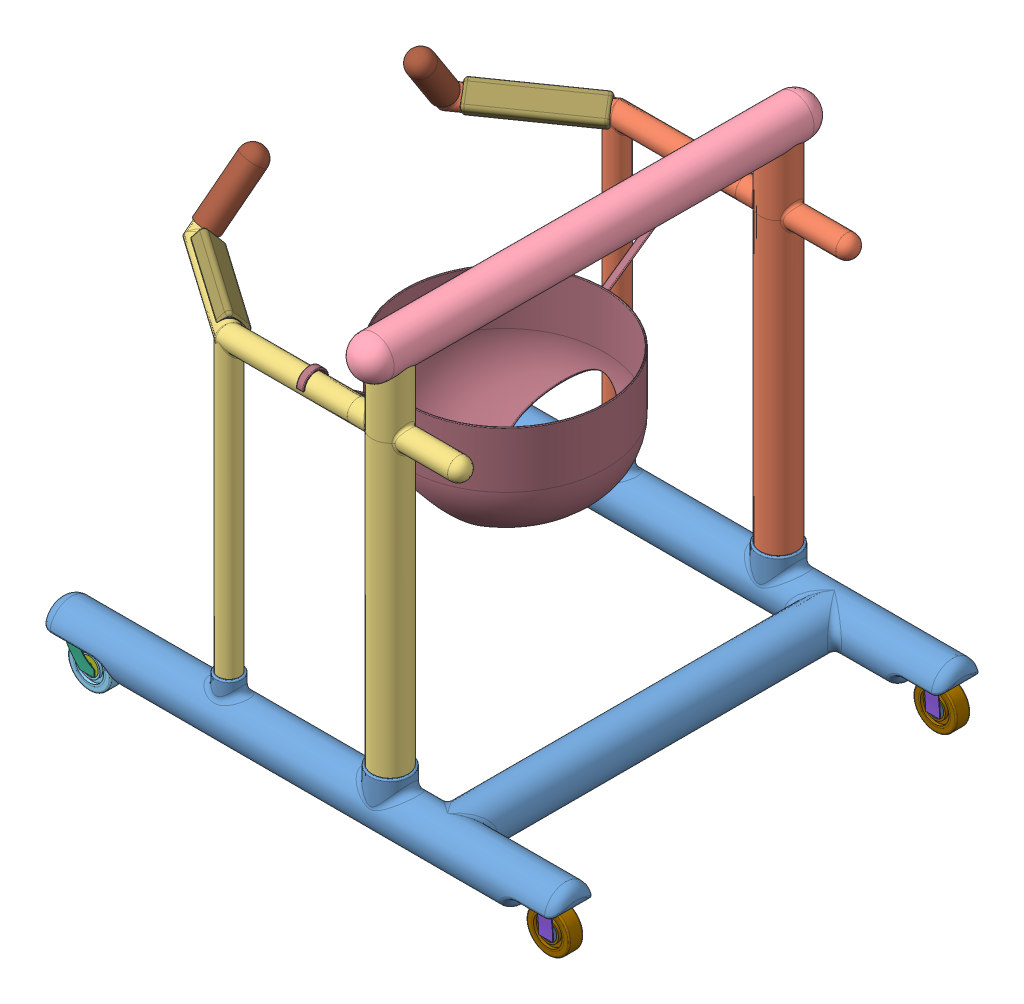
SolidWorks assembly Assem Collapse-Exploded Views, configuration Default. Lengths in mm.
Overall size (922.93 824.12 813.04).
41 component instances, 14 part files, 60 mates.
Components (placement in the parent):
- Base V5-1: Base V5 [Default] at (-126.4785 391.078 1010.3536) size (918.71 101.65 765.3)
- Side Left-1: Side Left [Default] at (402.939 968.928 324.5536) x (-1 0 0) z (0 0 -1) size (623.13 766.95 244.49)
- MirrorSide Left-3: MirrorSide Left [Default] at (400.5715 968.928 1010.3536) x (-1 0 0) z (0 0 -1) size (623.13 766.95 244.49)
- TopBarSupport-1: TopBarSupport [Default] at (457.5023 1094.5251 1073.8533) x (0.003452 0 -0.999994) z (0.999994 0 0.003452) size (812.8 71.12 71.12)
- Assem2 Front Wheel-1: Assem2 Front Wheel [Default] at (12.5906 315.4768 322.3492) x (0 0 1) z (-0.999997 0.002364 0) size (53.34 80.1 80.32)
  - Front Wheel-1: Front Wheel [Default] at (-10.3636 34.7825 75.6515) size (25.4 76.2 76.2)
  - Front Wheel Mountv2-1: Front Wheel Mountv2 [Default] at (18.654 50.0525 62.9876) x (1 0 0) z (0 -0.002364 0.999997) size (53.34 52.12 57.51)
  - Front Wheel BearingSet-1: Front Wheel BearingSet [Default] at (-10.3636 34.7825 75.6515) x (0 0.002364 -0.999997) z (1 0 0) size (31.75 31.75 25.4)
- Assem2 Front Wheel-2: Assem2 Front Wheel [Default] at (12.5906 315.4768 1008.1492) x (0 0 1) z (-0.999997 0.002364 0) size (53.34 80.1 80.32)
  - Front Wheel-1: Front Wheel [Default] at (-10.3636 34.7825 75.6515) size (25.4 76.2 76.2)
  - Front Wheel Mountv2-1: Front Wheel Mountv2 [Default] at (18.654 50.0525 62.9876) x (1 0 0) z (0 -0.002364 0.999997) size (53.34 52.12 57.51)
  - Front Wheel BearingSet-1: Front Wheel BearingSet [Default] at (-10.3636 34.7825 75.6515) x (0 0.002364 -0.999997) z (1 0 0) size (31.75 31.75 25.4)
- Assem2 Back Wheel-1: Assem2 Back Wheel [Default] at (706.4816 333.8846 330.834) x (0 0 -1) z (1 0 0) size (53.34 88.94 88.94)
  - Back Wheel Mountv2-1: Back Wheel Mountv2 [Default] at (22.7299 31.7935 30.6399) size (53.34 52.07 26.61)
  - Back Wheel-1: Back Wheel [Default] at (-6.5311 16.5535 43.3399) x (1 0 0) z (0 -0.184287 0.982872) size (25.4 76.2 76.2)
  - BackWheel Bairing Set-1: BackWheel Bairing Set [Default] at (18.8689 16.5535 43.3399) x (0 0 1) z (-1 0 0) size (31.75 31.75 25.4)
- Assem2 Back Wheel-2: Assem2 Back Wheel [Default] at (706.4816 333.8846 1016.634) x (0 0 -1) z (1 0 0) size (53.34 88.94 88.94)
  - Back Wheel Mountv2-1: Back Wheel Mountv2 [Default] at (22.7299 31.7935 30.6399) size (53.34 52.07 26.61)
  - Back Wheel-1: Back Wheel [Default] at (-6.5311 16.5535 43.3399) x (1 0 0) z (0 -0.184287 0.982872) size (25.4 76.2 76.2)
  - BackWheel Bairing Set-1: BackWheel Bairing Set [Default] at (18.8689 16.5535 43.3399) x (0 0 1) z (-1 0 0) size (31.75 31.75 25.4)
- Handle Covering v1-1: Handle Covering v1 [Default] at (-2.516 968.928 448.3888) x (0.979122 -0.193427 -0.062493) z (-0.062493 -0.578988 0.812937) size (43.18 127 43.18)
- Handle Covering v1-2: Handle Covering v1 [Default] at (-4.8834 968.928 886.5185) x (0.979122 -0.193427 0.062493) z (0.062493 0.578988 0.812937) size (43.18 127 43.18)
- Arm Covering v1-1: Arm Covering v1 [Default] at (88.3616 968.928 951.8093) x (0.819152 0 0.573576) z (-0.390769 0.732018 0.558076) size (190.83 24.3 45.72)
- Arm Covering v1-2: Arm Covering v1 [Default] at (92.2038 968.928 382.0653) x (0.819152 0 -0.573576) z (0.446291 -0.62816 0.637369) size (190.83 24.3 45.72)
- ChairPiece-1: ChairPiece [Default] at (318.9986 782.9456 667.2302) x (0 0.001708 0.999999) z (-1 0 0) size (730.43 346.85 355.6)
- WheelScrews-1: WheelScrews [Default] at (-97.2541 392.348 301.6936) x (-0.070113 0 0.997539) z (0.997539 0 0.070113) size (3.81 17.78 3.81)
- WheelScrews-2: WheelScrews [Default] at (-79.4885 392.348 301.6936) x (-0.070113 0 0.997539) z (0.997539 0 0.070113) size (3.81 17.78 3.81)
- WheelScrews-3: WheelScrews [Default] at (-79.4739 392.348 347.4136) x (-0.070113 0 0.997539) z (0.997539 0 0.070113) size (3.81 17.78 3.81)
- WheelScrews-4: WheelScrews [Default] at (-97.2685 392.348 347.4136) x (-0.070113 0 0.997539) z (0.997539 0 0.070113) size (3.81 17.78 3.81)
- WheelScrews-5: WheelScrews [Default] at (-79.4739 392.348 1033.2136) x (-0.070113 0 0.997539) z (0.997539 0 0.070113) size (3.81 17.78 3.81)
- WheelScrews-7: WheelScrews [Default] at (-97.2685 392.348 1033.2136) x (-0.070113 0 0.997539) z (0.997539 0 0.070113) size (3.81 17.78 3.81)
- WheelScrews-8: WheelScrews [Default] at (-79.4885 392.348 987.4936) x (-0.070113 0 0.997539) z (0.997539 0 0.070113) size (3.81 17.78 3.81)
- WheelScrews-9: WheelScrews [Default] at (-97.2541 392.348 987.4936) x (-0.070113 0 0.997539) z (0.997539 0 0.070113) size (3.81 17.78 3.81)
- WheelScrews-10: WheelScrews [Default] at (740.9315 392.348 347.4136) x (-0.837169 0 -0.546944) z (-0.546944 0 0.837169) size (3.81 17.78 3.81)
- WheelScrews-11: WheelScrews [Default] at (758.7115 392.348 347.4136) x (-0.837169 0 -0.546944) z (-0.546944 0 0.837169) size (3.81 17.78 3.81)
- WheelScrews-14: WheelScrews [Default] at (758.7115 392.348 301.6936) x (-0.837169 0 -0.546944) z (-0.546944 0 0.837169) size (3.81 17.78 3.81)
- WheelScrews-15: WheelScrews [Default] at (740.9315 392.348 301.6936) x (-0.837169 0 -0.546944) z (-0.546944 0 0.837169) size (3.81 17.78 3.81)
- WheelScrews-16: WheelScrews [Default] at (740.9315 392.348 1033.2136) x (-0.837169 0 -0.546944) z (-0.546944 0 0.837169) size (3.81 17.78 3.81)
- WheelScrews-18: WheelScrews [Default] at (758.7115 392.348 987.4936) x (-0.837169 0 -0.546944) z (-0.546944 0 0.837169) size (3.81 17.78 3.81)
- WheelScrews-19: WheelScrews [Default] at (740.9315 392.348 987.4936) x (-0.837169 0 -0.546944) z (-0.546944 0 0.837169) size (3.81 17.78 3.81)
- WheelScrews-20: WheelScrews [Default] at (758.7115 392.348 1033.2136) x (-0.837169 0 -0.546944) z (-0.546944 0 0.837169) size (3.81 17.78 3.81)
Mates (geometry in assembly coordinates):
- Tangent1: tangent aligned: cylinder of Base V5-1 through (635.5215 391.078 324.5536) axis (-1 0 0) radius 31.75; sphere of Side Left-1
- Concentric1: concentric aligned: cylinder of Base V5-1 through (460.089 352.977 324.5536) axis (0 1 0) radius 31.75; cylinder of Side Left-1 through (460.089 359.328 324.5536) axis (0 1 0) radius 31.75
- Concentric2: concentric anti-aligned: cylinder of Base V5-1 through (174.339 391.078 324.5536) axis (0 1 0) radius 19.05; cylinder of Side Left-1 through (174.339 968.928 324.5536) axis (0 -1 0) radius 19.05
- Tangent2: tangent aligned: cylinder of Base V5-1 through (635.5215 391.078 1010.3536) axis (-1 0 0) radius 31.75; sphere of MirrorSide Left-3
- Concentric3: concentric aligned: cylinder of Base V5-1 through (457.7215 352.977 1010.3536) axis (0 1 0) radius 31.75; cylinder of MirrorSide Left-3 through (457.7215 359.328 1010.3536) axis (0 1 0) radius 31.75
- Concentric4: concentric anti-aligned: cylinder of Base V5-1 through (171.9715 391.078 1010.3536) axis (0 1 0) radius 19.05; cylinder of MirrorSide Left-3 through (171.9715 968.928 1010.3536) axis (0 -1 0) radius 19.05
- Tangent3: tangent aligned: sphere of MirrorSide Left-3; cylinder of TopBarSupport-1 through (460.2205 1094.5251 286.458) axis (-0.003452 0 0.999994) radius 31.75
- Tangent4: tangent aligned: sphere of Side Left-1; cylinder of TopBarSupport-1 through (460.2205 1094.5251 286.458) axis (-0.003452 0 0.999994) radius 31.75
- Concentric5: concentric aligned: cylinder of MirrorSide Left-3 through (457.7215 968.928 1010.3536) axis (0 1 0) radius 31.75; cylinder of TopBarSupport-1 through (457.7215 1058.9641 1010.3536) axis (0 1 0) radius 31.75
- Concentric6: concentric: sphere of Side Left-1; sphere of Handle Covering v1-1
- Concentric7: concentric anti-aligned: cylinder of Side Left-1 through (-10.1378 937.7174 425.5741) axis (0.193427 0.79206 0.578988) radius 19.05; cylinder of Handle Covering v1-1 through (24.5058 1079.5788 529.2735) axis (-0.193427 -0.79206 -0.578988) radius 19.05
- Concentric8: concentric: sphere of MirrorSide Left-3; sphere of Handle Covering v1-2
- Concentric9: concentric anti-aligned: cylinder of MirrorSide Left-3 through (-12.5053 937.7174 909.3332) axis (0.193427 0.79206 -0.578988) radius 19.05; cylinder of Handle Covering v1-2 through (22.1383 1079.5788 805.6338) axis (-0.193427 -0.79206 0.578988) radius 19.05
- Concentric10: concentric aligned: cylinder of MirrorSide Left-3 through (184.1534 968.928 1018.8835) axis (-0.819152 0 -0.573576) radius 19.05; cylinder of Arm Covering v1-1 through (166.3866 968.928 1006.4431) axis (-0.819152 0 -0.573576) radius 19.05
- Concentric11: concentric aligned: cylinder of Side Left-1 through (186.5208 968.928 316.0238) axis (-0.819152 0 0.573576) radius 19.05; cylinder of Arm Covering v1-2 through (170.2288 968.928 327.4316) axis (-0.819152 0 0.573576) radius 19.05
- Coincident1: coincident anti-aligned: plane of Base V5-1 through (-126.4785 392.348 1010.3536) normal (0 -1 0); plane of Assem2 Front Wheel-1/Front Wheel Mountv2-1 through (-50.2785 392.348 341.0032) normal (0 1 0)
- Coincident2: coincident anti-aligned: plane of Base V5-1 through (-101.0785 392.348 297.8836) normal (0 0 1); plane of Assem2 Front Wheel-1/Front Wheel Mountv2-1 through (-50.2785 365.678 297.8836) normal (0 0 -1)
- Coincident3: coincident anti-aligned: plane of Base V5-1 through (-101.0785 392.348 351.2236) normal (1 0 0); plane of Assem2 Front Wheel-1/Front Wheel Mountv2-1 through (-101.0785 392.348 351.2236) normal (-1 0 0)
- Coincident4: coincident anti-aligned: plane of Base V5-1 through (-126.4785 392.348 1010.3536) normal (0 -1 0); plane of Assem2 Front Wheel-2/Front Wheel Mountv2-1 through (-50.2785 392.348 1026.8032) normal (0 1 0)
- Coincident5: coincident anti-aligned: plane of Base V5-1 through (-101.0785 392.348 1037.0236) normal (1 0 0); plane of Assem2 Front Wheel-2/Front Wheel Mountv2-1 through (-101.0785 392.348 1037.0236) normal (-1 0 0)
- Coincident6: coincident anti-aligned: plane of Base V5-1 through (-101.0785 392.348 1037.0236) normal (0 0 -1); plane of Assem2 Front Wheel-2/Front Wheel Mountv2-1 through (-50.2785 365.678 1037.0236) normal (0 0 1)
- Coincident7: coincident anti-aligned: plane of Base V5-1 through (-126.4785 392.348 1010.3536) normal (0 -1 0); plane of Assem2 Back Wheel-2/Back Wheel Mountv2-1 through (737.1215 392.348 993.9041) normal (0 1 0)
- Coincident8: coincident: plane of Base V5-1 through (762.5215 392.348 1037.0236) normal (-1 0 0); line of Assem2 Back Wheel-2/Back Wheel Mountv2-1 through (762.5215 392.094 983.9376) axis (0 0 1)
- Coincident9: coincident anti-aligned: plane of Base V5-1 through (737.1215 392.348 1037.0236) normal (0 0 -1); plane of Assem2 Back Wheel-2/Back Wheel Mountv2-1 through (737.1215 365.678 1037.0236) normal (0 0 1)
- Coincident10: coincident anti-aligned: plane of Base V5-1 through (-126.4785 392.348 1010.3536) normal (0 -1 0); plane of Assem2 Back Wheel-1/Back Wheel Mountv2-1 through (737.1215 392.348 308.1041) normal (0 1 0)
- Coincident11: coincident: plane of Base V5-1 through (762.5215 392.348 351.2236) normal (-1 0 0); line of Assem2 Back Wheel-1/Back Wheel Mountv2-1 through (762.5215 392.094 298.1376) axis (0 0 1)
- Coincident12: coincident anti-aligned: plane of Base V5-1 through (737.1215 392.348 297.8836) normal (0 0 1); plane of Assem2 Back Wheel-1/Back Wheel Mountv2-1 through (737.1215 365.678 297.8836) normal (0 0 -1)
- Coincident16: coincident anti-aligned: plane of Base V5-1 through (-97.2685 408.858 301.6936) normal (0 -1 0); plane of WheelScrews-1 through (-97.2541 408.858 301.6936) normal (0 1 0)
- Concentric13: concentric aligned: cylinder of Assem2 Front Wheel-1/Front Wheel Mountv2-1 through (-97.2541 340.277 301.6936) axis (0 1 0) radius 1.905; cylinder of WheelScrews-1 through (-97.2541 391.078 301.6936) axis (0 1 0) radius 1.905
- Coincident18: coincident anti-aligned: plane of Base V5-1 through (-79.4885 408.858 301.6936) normal (0 -1 0); plane of WheelScrews-2 through (-79.4885 408.858 301.6936) normal (0 1 0)
- Concentric14: concentric aligned: cylinder of Assem2 Front Wheel-1/Front Wheel Mountv2-1 through (-79.4885 340.277 301.6936) axis (0 1 0) radius 1.905; cylinder of WheelScrews-2 through (-79.4885 391.078 301.6936) axis (0 1 0) radius 1.905
- Coincident19: coincident anti-aligned: plane of Base V5-1 through (-97.2685 408.858 347.4136) normal (0 -1 0); plane of WheelScrews-4 through (-97.2685 408.858 347.4136) normal (0 1 0)
- Concentric15: concentric aligned: cylinder of Assem2 Front Wheel-1/Front Wheel Mountv2-1 through (-97.2685 340.277 347.4136) axis (0 1 0) radius 1.905; cylinder of WheelScrews-4 through (-97.2685 391.078 347.4136) axis (0 1 0) radius 1.905
- Coincident20: coincident anti-aligned: plane of Base V5-1 through (-79.4885 408.858 347.4136) normal (0 -1 0); plane of WheelScrews-3 through (-79.4739 408.858 347.4136) normal (0 1 0)
- Concentric16: concentric aligned: cylinder of Assem2 Front Wheel-1/Front Wheel Mountv2-1 through (-79.4739 340.277 347.4136) axis (0 1 0) radius 1.905; cylinder of WheelScrews-3 through (-79.4739 391.078 347.4136) axis (0 1 0) radius 1.905
- Coincident25: coincident anti-aligned: plane of Base V5-1 through (-97.2685 408.858 987.4936) normal (0 -1 0); plane of WheelScrews-9 through (-97.2541 408.858 987.4936) normal (0 1 0)
- Coincident26: coincident aligned: circle of Assem2 Front Wheel-2/Front Wheel Mountv2-1; cylinder of WheelScrews-9 through (-97.2541 391.078 987.4936) axis (0 1 0) radius 1.905
- Coincident27: coincident anti-aligned: plane of Base V5-1 through (-79.4885 408.858 987.4936) normal (0 -1 0); plane of WheelScrews-8 through (-79.4885 408.858 987.4936) normal (0 1 0)
- Concentric21: concentric aligned: cylinder of Assem2 Front Wheel-2/Front Wheel Mountv2-1 through (-79.4885 340.277 987.4936) axis (0 1 0) radius 1.905; cylinder of WheelScrews-8 through (-79.4885 391.078 987.4936) axis (0 1 0) radius 1.905
- Coincident29: coincident anti-aligned: plane of Base V5-1 through (-97.2685 408.858 1033.2136) normal (0 -1 0); plane of WheelScrews-7 through (-97.2685 408.858 1033.2136) normal (0 1 0)
- Concentric22: concentric aligned: cylinder of Assem2 Front Wheel-2/Front Wheel Mountv2-1 through (-97.2685 340.277 1033.2136) axis (0 1 0) radius 1.905; cylinder of WheelScrews-7 through (-97.2685 391.078 1033.2136) axis (0 1 0) radius 1.905
- Coincident30: coincident anti-aligned: plane of Base V5-1 through (-79.4885 408.858 1033.2136) normal (0 -1 0); plane of WheelScrews-5 through (-79.4739 408.858 1033.2136) normal (0 1 0)
- Concentric23: concentric aligned: cylinder of Assem2 Front Wheel-2/Front Wheel Mountv2-1 through (-79.4739 340.277 1033.2136) axis (0 1 0) radius 1.905; cylinder of WheelScrews-5 through (-79.4739 391.078 1033.2136) axis (0 1 0) radius 1.905
- Coincident31: coincident anti-aligned: plane of Base V5-1 through (758.7115 408.858 347.4136) normal (0 -1 0); plane of WheelScrews-11 through (758.7115 408.858 347.4136) normal (0 1 0)
- Concentric24: concentric aligned: cylinder of Assem2 Back Wheel-1/Back Wheel Mountv2-1 through (758.7115 340.277 347.4136) axis (0 1 0) radius 1.905; cylinder of WheelScrews-11 through (758.7115 391.078 347.4136) axis (0 1 0) radius 1.905
- Coincident32: coincident anti-aligned: plane of Base V5-1 through (740.9315 408.858 347.4136) normal (0 -1 0); circle of WheelScrews-10
- Coincident33: coincident anti-aligned: cylinder of Assem2 Back Wheel-1/Back Wheel Mountv2-1 through (740.9315 340.277 347.4136) axis (0 1 0) radius 1.905; circle of WheelScrews-10
- Coincident36: coincident anti-aligned: plane of Base V5-1 through (758.7115 408.858 301.6936) normal (0 -1 0); plane of WheelScrews-14 through (758.7115 408.858 301.6936) normal (0 1 0)
- Concentric25: concentric aligned: cylinder of Assem2 Back Wheel-1/Back Wheel Mountv2-1 through (758.7115 340.277 301.6936) axis (0 1 0) radius 1.905; cylinder of WheelScrews-14 through (758.7115 391.078 301.6936) axis (0 1 0) radius 1.905
- Coincident37: coincident anti-aligned: plane of Base V5-1 through (740.9315 408.858 301.6936) normal (0 -1 0); plane of WheelScrews-15 through (740.9315 408.858 301.6936) normal (0 1 0)
- Concentric26: concentric aligned: cylinder of Assem2 Back Wheel-1/Back Wheel Mountv2-1 through (740.9315 340.277 301.6936) axis (0 1 0) radius 1.905; cylinder of WheelScrews-15 through (740.9315 391.078 301.6936) axis (0 1 0) radius 1.905
- Coincident38: coincident anti-aligned: plane of Base V5-1 through (758.7115 408.858 1033.2136) normal (0 -1 0); plane of WheelScrews-20 through (758.7115 408.858 1033.2136) normal (0 1 0)
- Concentric27: concentric aligned: cylinder of Assem2 Back Wheel-2/Back Wheel Mountv2-1 through (758.7115 340.277 1033.2136) axis (0 1 0) radius 1.905; cylinder of WheelScrews-20 through (758.7115 391.078 1033.2136) axis (0 1 0) radius 1.905
- Coincident39: coincident anti-aligned: plane of Base V5-1 through (740.9315 408.858 1033.2136) normal (0 -1 0); plane of WheelScrews-16 through (740.9315 408.858 1033.2136) normal (0 1 0)
- Concentric28: concentric aligned: cylinder of Assem2 Back Wheel-2/Back Wheel Mountv2-1 through (740.9315 340.277 1033.2136) axis (0 1 0) radius 1.905; cylinder of WheelScrews-16 through (740.9315 391.078 1033.2136) axis (0 1 0) radius 1.905
- Coincident40: coincident anti-aligned: plane of Base V5-1 through (758.7115 408.858 987.4936) normal (0 -1 0); plane of WheelScrews-18 through (758.7115 408.858 987.4936) normal (0 1 0)
- Concentric29: concentric aligned: cylinder of Assem2 Back Wheel-2/Back Wheel Mountv2-1 through (758.7115 340.277 987.4936) axis (0 1 0) radius 1.905; cylinder of WheelScrews-18 through (758.7115 391.078 987.4936) axis (0 1 0) radius 1.905
- Coincident41: coincident anti-aligned: plane of Base V5-1 through (740.9315 408.858 987.4936) normal (0 -1 0); plane of WheelScrews-19 through (740.9315 408.858 987.4936) normal (0 1 0)
- Concentric30: concentric aligned: cylinder of Assem2 Back Wheel-2/Back Wheel Mountv2-1 through (740.9315 340.277 987.4936) axis (0 1 0) radius 1.905; cylinder of WheelScrews-19 through (740.9315 391.078 987.4936) axis (0 1 0) radius 1.905
- Concentric39: concentric aligned: cylinder of Side Left-1 through (402.939 968.928 324.5536) axis (-1 0 0) radius 19.05; cylinder of ChairPiece-1 through (496.7996 968.928 324.5536) axis (-1 0 0) radius 19.05
